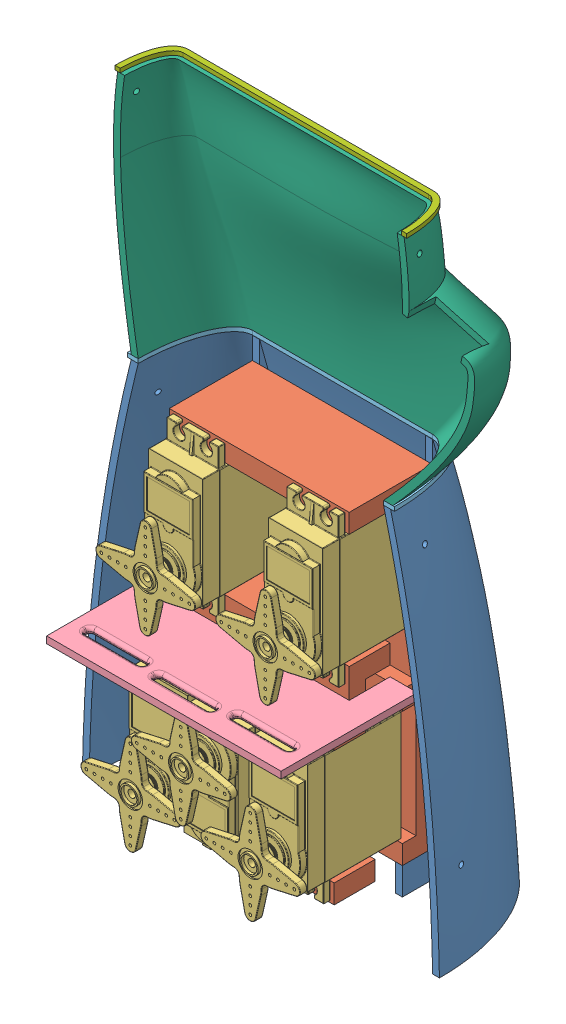
SolidWorks assembly Back Assembly, configuration Default. Lengths in mm.
Overall size (148.72 230.56 93.41).
12 component instances, 7 part files, 12 mates.
Components (placement in the parent):
- Arm Back-1: Arm Back [Default] at (-6.5809 28.2915 147.1931) size (139.6 140.5 63.13)
- Servo Assembly-1: Servo Assembly [Default] at (-41.7016 175.9089 84.6263) x (1 0 0) z (0 -1 0) size (86 65.5 122.79)
  - Bed-1: Bed [Default] at (2.1207 32.6668 137.6174) size (66 39.5 122)
  - S3003-2: S3003 [Default] at (35.1207 44.6668 109.6174) x (0 0 -1) z (1 0 0) size (56.04 47.8 36.5)
  - S3003-3: S3003 [Default] at (13.1207 41.1668 109.6174) x (0 0 1) z (-1 0 0) size (56.04 47.8 36.5)
  - S3003-4: S3003 [Default] at (57.1207 41.1668 109.6174) x (0 0 1) z (-1 0 0) size (56.04 47.8 36.5)
  - S3003-5: S3003 [Default] at (13.1207 35.6668 43.6174) x (0 0 1) z (-1 0 0) size (56.04 47.8 36.5)
  - S3003-6: S3003 [Default] at (57.1207 35.6668 43.6174) x (0 0 1) z (-1 0 0) size (56.04 47.8 36.5)
  - String holder-2: String holder [Default] at (2.1207 60.1668 75.3674) x (1 0 0) z (0 -1 0) size (86 2.5 50)
- Hand Bottom Decoration Back-1: Hand Bottom Decoration Back [Default] at (-6.5809 168.2915 147.1931) size (104.1 1.5 40.1)
- Hand Back-1: Hand Back [Default] at (-6.5809 169.7915 147.1931) size (139.36 90.89 40.4)
- Hand Top Decoration-1: Hand Top Decoration [Default] at (-6.5809 257.2915 147.1931) size (110.31 1.5 21.89)
Mates (geometry in assembly coordinates):
- Coincident1: coincident anti-aligned: plane of Arm Back-1 through (-39.5809 38.2915 128.2931) normal (0 1 0); plane of Servo Assembly-1/Bed-1 through (-39.5809 38.2915 123.2931) normal (0 -1 0)
- Coincident2: coincident aligned: plane of Arm Back-1 through (-39.5809 168.2915 117.2931) normal (-1 0 0); plane of Servo Assembly-1/Bed-1 through (-39.5809 38.2915 123.2931) normal (-1 0 0)
- Coincident3: coincident anti-aligned: line of Arm Back-1 through (-39.5809 38.2915 117.2931) axis (0 1 0); line of Servo Assembly-1/Bed-1 through (-39.5809 160.2915 117.2931) axis (0 -1 0)
- Coincident4: coincident anti-aligned: plane of Arm Back-1 through (-6.5809 168.2915 147.1931) normal (0 1 0); plane of Hand Bottom Decoration Back-1 through (-39.5809 168.2915 147.1931) normal (0 -1 0)
- Coincident5: coincident: point of Arm Back-1; point of Hand Bottom Decoration Back-1
- Coincident6: coincident aligned: line of Arm Back-1 through (-39.5809 168.2915 177.1931) axis (1 0 0); line of Hand Bottom Decoration Back-1 through (-39.5809 168.2915 177.1931) axis (1 0 0)
- Coincident7: coincident anti-aligned: plane of Hand Bottom Decoration Back-1 through (-39.5809 169.7915 147.1931) normal (0 1 0); plane of Hand Back-1 through (-39.5809 169.7915 147.1931) normal (0 -1 0)
- Coincident17: coincident aligned: plane of Arm Back-1 through (66.4098 168.3034 147.1931) normal (0 0 1); plane of Hand Back-1 through (97.5535 257.3034 147.1931) normal (0 0 1)
- Coincident18: coincident: unknown of Hand Bottom Decoration Back-1
- Coincident19: coincident anti-aligned: plane of Hand Back-1 through (-51.5809 257.2915 147.1931) normal (0 1 0); plane of Hand Top Decoration-1 through (-51.5809 257.2915 147.1931) normal (0 -1 0)
- Coincident20: coincident: point of Hand Back-1; point of Hand Top Decoration-1
- Coincident21: coincident aligned: line of Hand Back-1 through (-51.5809 257.2915 162.1931) axis (1 0 0); line of Hand Top Decoration-1 through (-51.5809 257.2915 162.1931) axis (1 0 0)
